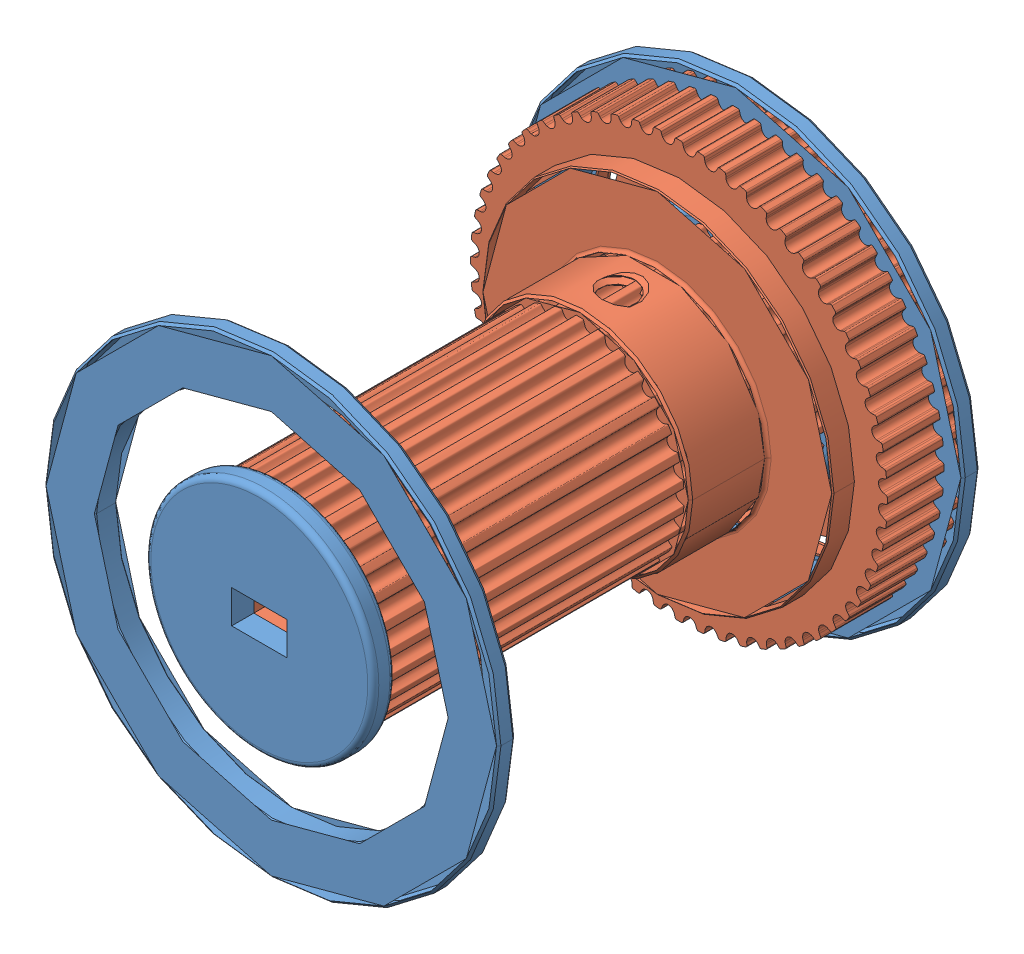
SolidWorks assembly Assem2, configuration Default. Lengths in mm.
Overall size (20.61 20.61 44).
3 component instances, 2 part files, 5 mates.
Components (placement in the parent):
- gear kecil 20 bawah-1: gear kecil 20 bawah [Default] at origin size (41.15 41.15 3)
- puley kecil 20-1: puley kecil 20 [Default] at (0 0 -2) size (37.7 37.7 45)
- gear kecil 20 bawah-2: gear kecil 20 bawah [Default] at (0 0 42) size (41.15 41.15 3)
Mates (geometry in assembly coordinates):
- Coincident1: coincident: line of gear kecil 20 bawah-1 through (2.5 1.5 3) axis (-1 0 0); line of puley kecil 20-1 through (2.5 1.5 3) axis (-1 0 0)
- Coincident4: coincident: plane of gear kecil 20 bawah-1 through (0 0 3) normal (0 0 1); plane of puley kecil 20-1 through (-3.4759 -8.7166 3) normal (0 0 -1)
- Coincident6: coincident aligned: line of gear kecil 20 bawah-1 through (2.5 -1.5 3) axis (0 1 0); line of puley kecil 20-1 through (2.5 -1.5 3) axis (0 1 0)
- Coincident7: coincident: line of puley kecil 20-1 through (2.5 -1.5 43) axis (0 1 0); line of gear kecil 20 bawah-2 through (2.5 -1.5 43) axis (0 1 0)
- Coincident8: coincident anti-aligned: line of puley kecil 20-1 through (-2.5 -1.5 43) axis (1 0 0); line of gear kecil 20 bawah-2 through (2.5 -1.5 43) axis (-1 0 0)
